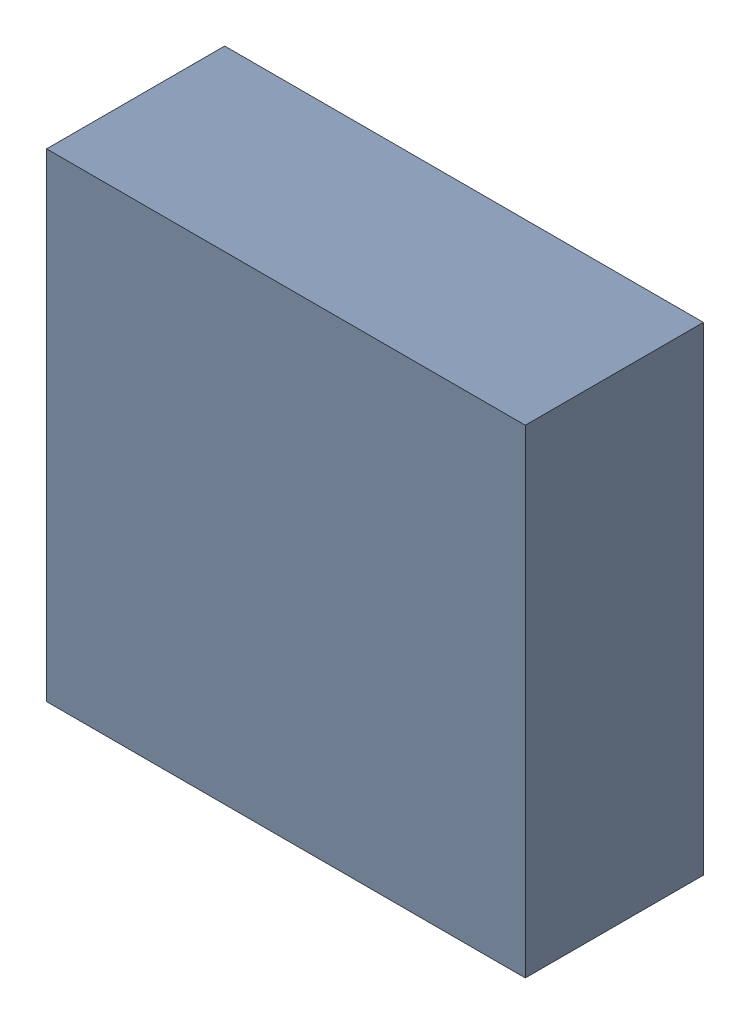
SolidWorks assembly Q4, configuration ﾃﾞﾌｫﾙﾄ. Lengths in mm.
Overall size (2.15 2.15 0.8).
2 component instances, 1 part files, 0 mates.
Components (placement in the parent):
- 689261240-1: 689261240 [ﾃﾞﾌｫﾙﾄ] at (21.5 73.25 0) size (2.15 2.15 0.8)
  - Extruded_30-1: Extruded_30 [ﾃﾞﾌｫﾙﾄ] at origin size (2.15 2.15 0.8)
